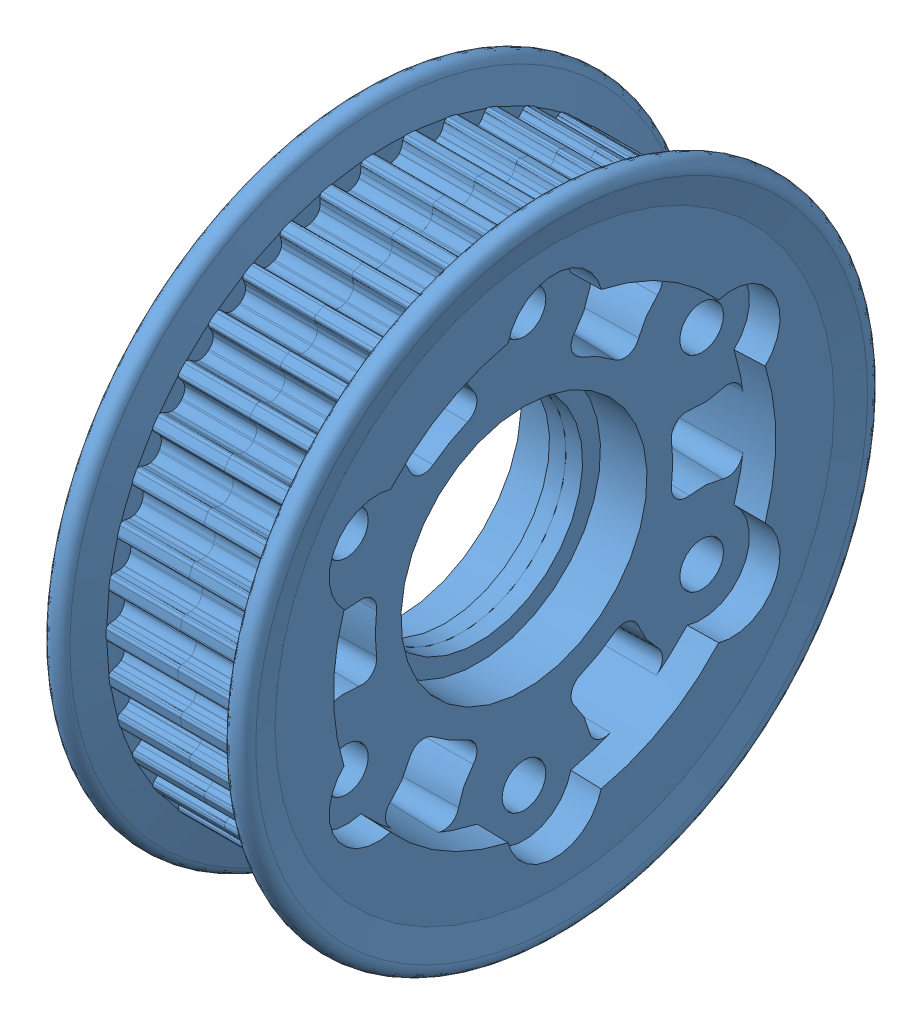
SolidWorks assembly 2.6Inch_Plastic_Pulley, configuration Default. Lengths in mm.
Overall size (23.46 74.23 74.23).
2 component instances, 1 part files, 3 mates.
Components (placement in the parent):
- am-2234_2.6Inch_Plastic_Pulley-1: am-2234_2.6Inch_Plastic_Pulley [Default] at origin size (13 74.23 74.23)
- am-2234_2.6Inch_Plastic_Pulley-2: am-2234_2.6Inch_Plastic_Pulley [Default] at (16.6624 0 0) x (-1 0 0) z (0 0.000084 1) size (13 74.23 74.23)
Mates (geometry in assembly coordinates):
- Coincident1: coincident anti-aligned: plane of am-2234_2.6Inch_Plastic_Pulley-1 through (8.3312 32.198 0.1238) normal (1 0 0); plane of am-2234_2.6Inch_Plastic_Pulley-2 through (8.3312 -32.198 0.1265) normal (-1 0 0)
- Concentric1: concentric aligned: circle of am-2234_2.6Inch_Plastic_Pulley-1; circle of am-2234_2.6Inch_Plastic_Pulley-2
- Concentric2: concentric aligned: circle of am-2234_2.6Inch_Plastic_Pulley-1; circle of am-2234_2.6Inch_Plastic_Pulley-2
